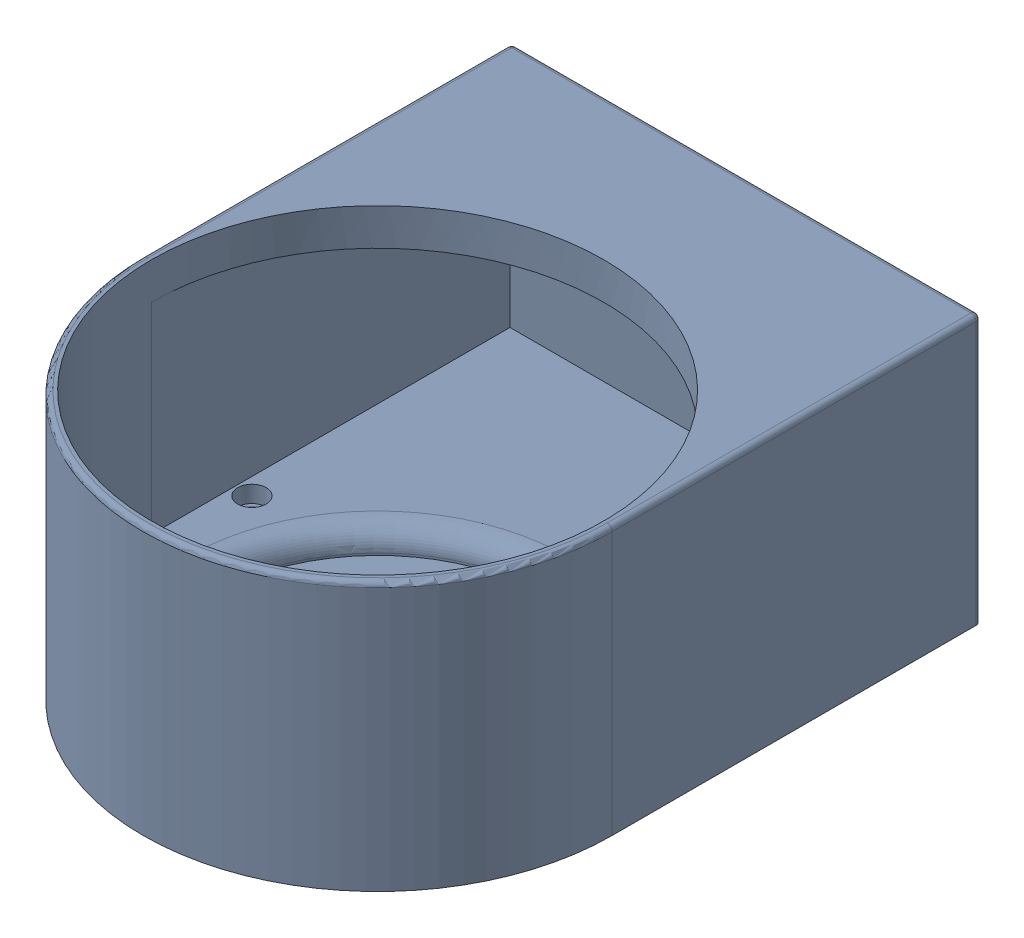
SolidWorks assembly B2647, configuration Default. Lengths in mm.
Overall size (280 160 360).
11 component instances, 3 part files, 0 mates.
Components (placement in the parent):
- B2123_2-1: B2123_2 [Default] at origin size (280 160 360)
- B1995-1: B1995 [woLabels] at (-140 0 -220) x (0 0 1) z (0 1 0) size (239.39 157.62 264.32) (suppressed, hidden)
  - B1998-1: B1998 [X] x (0 0 -1) z (1 0 0) size (28.64 28.64 210)
  - B1998-2: B1998 [Y] x (0 0 1) z (0 1 0) size (28.64 28.64 110)
  - B1998-3: B1998 [Z] at origin size (28.64 28.64 260)
  - B1999-2: B1999 [100] at (0 0 197.2124) x (0 0 -1) z (0.268665 -0.963234 0) size (50 78.75 105)
- B1995-2: B1995 [woLabels] at (0 346 0) x (0 0 1) z (0 1 0) size (239.39 157.62 264.32) (suppressed, hidden)
  - B1998-1: B1998 [X] x (0 0 -1) z (1 0 0) size (28.64 28.64 210)
  - B1998-2: B1998 [Y] x (0 0 1) z (0 1 0) size (28.64 28.64 110)
  - B1998-3: B1998 [Z] at origin size (28.64 28.64 260)
  - B1999-2: B1999 [100] at (0 0 197.2124) x (0 0 -1) z (0.268665 -0.963234 0) size (50 78.75 105)
